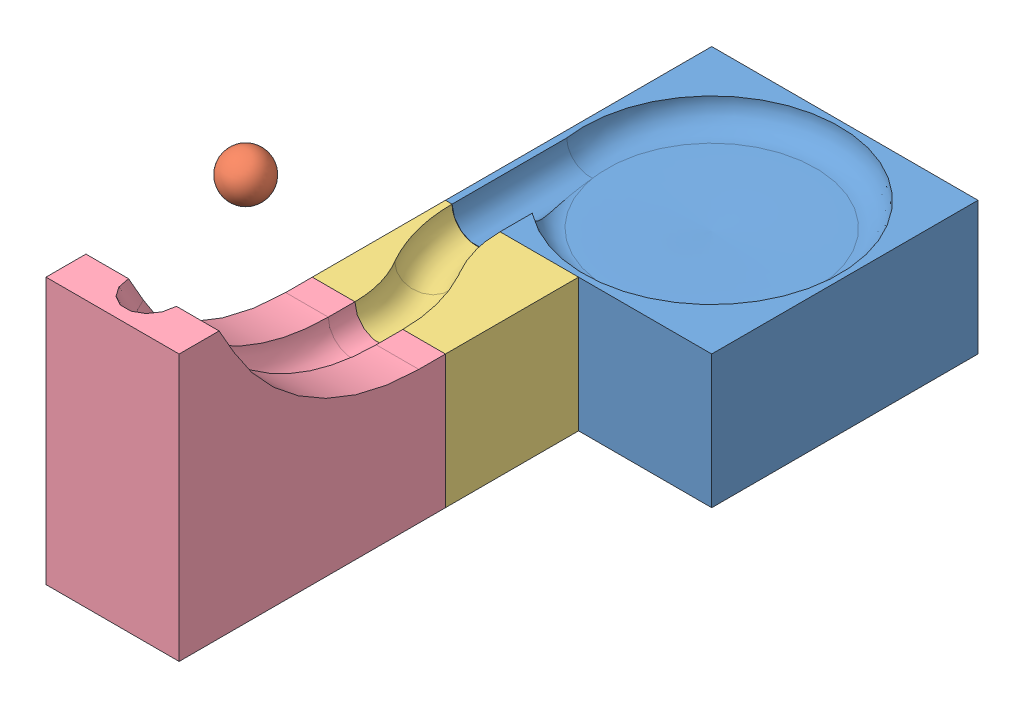
SolidWorks assembly marble run with ramp, configuration Default. Lengths in mm.
Overall size (100 115.51 250).
4 component instances, 4 part files, 9 mates.
Components (placement in the parent):
- Teil1^marble run with ramp-1: Teil1^marble run with ramp [Standard] at origin size (100 52.96 100) (virtual)
- Kopie von Teil2^marble run with ramp-1: Kopie von Teil2^marble run with ramp [Standard] at (-38.7887 107.0085 136.2137) size (17 17 17) (virtual)
- Teil4^marble run with ramp-1: Teil4^marble run with ramp [Standard] at (-25 0 75) size (50 50 50.18) (virtual)
- Teil5^marble run with ramp-1: Teil5^marble run with ramp [Standard] at (-25 0 100) x (0 0 -1) z (1 0 0) size (100 100 50) (virtual)
Mates (geometry in assembly coordinates):
- Deckungsgleich1: coincident aligned: plane of Teil1^Grafitationstrichter-1 through (-50 50 50) normal (-1 0 0); plane of Teil4^Grafitationstrichter-1 through (-50 50 100) normal (-1 0 0)
- Deckungsgleich2: coincident aligned: plane of Teil1^Grafitationstrichter-1 through (0 0 0) normal (0 -1 0); plane of Teil4^Grafitationstrichter-1 through (-25 0 75) normal (0 -1 0)
- Deckungsgleich3: coincident anti-aligned: plane of Teil1^Grafitationstrichter-1 through (-50 50 50) normal (0 0 1); plane of Teil4^Grafitationstrichter-1 through (-50 50 50) normal (0 0 -1)
- Deckungsgleich10: coincident anti-aligned: plane of Teil4^Grafitationstrichter-1 through (-50 50 100) normal (0 0 1); plane of Teil5^marble run with ramp-1 through (0 0 100) normal (0 0 -1)
- Deckungsgleich11: coincident aligned: plane of Teil4^Grafitationstrichter-1 through (-25 0 75) normal (0 -1 0); plane of Teil5^marble run with ramp-1 through (0 0 200) normal (0 -1 0)
- Deckungsgleich12: coincident aligned: plane of Teil4^Grafitationstrichter-1 through (-50 50 100) normal (-1 0 0); plane of Teil5^marble run with ramp-1 through (-50 130 110) normal (-1 0 0)
- Deckungsgleich13: coincident aligned: circle of Teil1^Grafitationstrichter-1; circle of Teil5^Grafitationstrichter-1
- Deckungsgleich14: coincident aligned: plane of Teil1^Grafitationstrichter-1 through (0 0 0) normal (0 -1 0); plane of Teil5^Grafitationstrichter-1 through (-12 0 150) normal (0 -1 0)
- Deckungsgleich16: coincident aligned: plane of Teil1^Grafitationstrichter-1 through (0 0 0) normal (0 -1 0); plane of Teil5^marble run with ramp-1 through (0 0 200) normal (0 -1 0)
